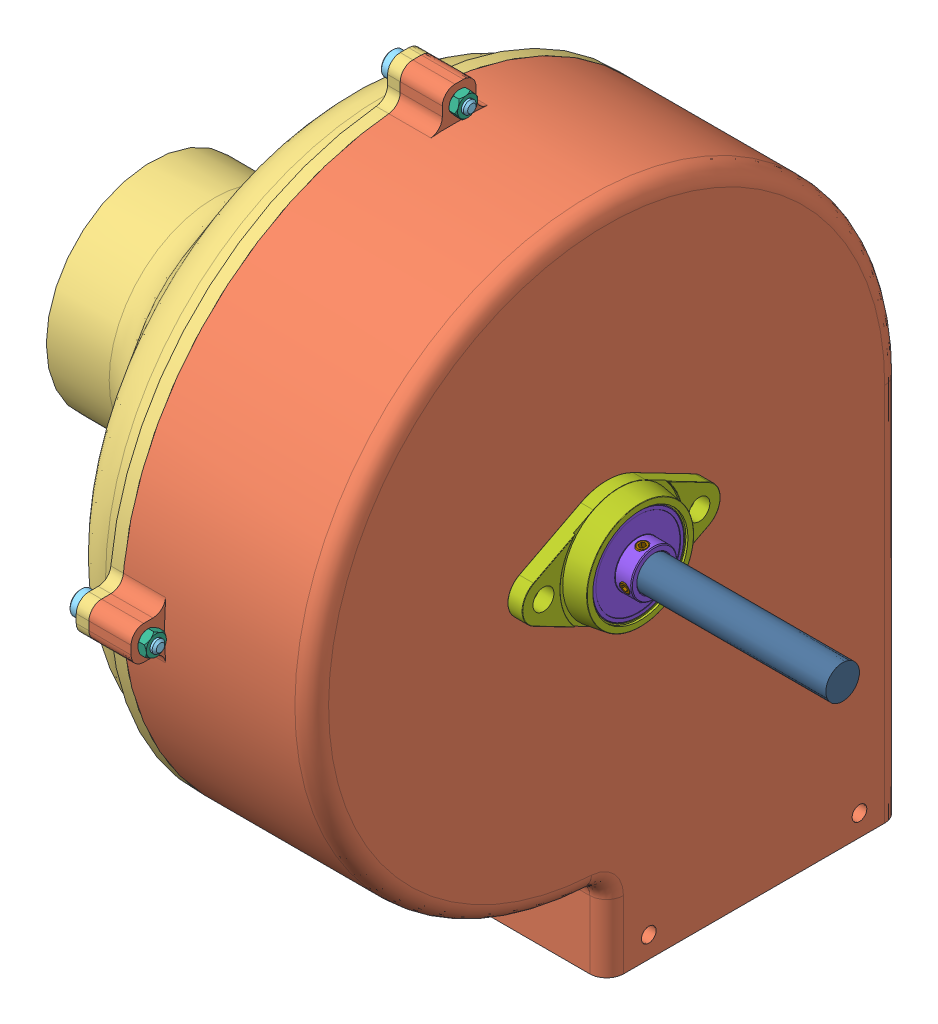
SolidWorks assembly blower, configuration Default. Lengths in mm.
Overall size (164 167.89 155.89).
20 component instances, 10 part files, 34 mates.
Components (placement in the parent):
- impeller-1: impeller [Default] at (-69.6752 187.7054 -326.6035) x (0 0.998096 -0.061685) z (0 0.061685 0.998096) size (118 42 118)
- bottom-1: bottom [external-motor] at (-57.6752 187.7054 -326.6035) x (0 0 -1) z (0 1 0) size (155.89 45 167.89)
- top-1: top [Default] at (-102.6752 187.7054 -326.6035) x (0 -1 0) z (0 0 -1) size (167.89 63 155.89)
- rotating-body^blower-1: rotating-body^blower [Default] at (-69.6752 187.7054 -326.6035) x (0 -0.998096 0.061685) z (1 0 0) size (120 120 42) (virtual)
- m3-socket-16-1: m3-socket-16 [Default] at (-108.6752 114.164 -400.6035) size (19 5.5 5.5)
- m3-socket-16-2: m3-socket-16 [Default] at (-108.6752 114.164 -322.6035) size (19 5.5 5.5)
- m3-socket-16-3: m3-socket-16 [Default] at (-108.6752 183.7054 -400.6035) size (19 5.5 5.5)
- m3-socket-16-4: m3-socket-16 [Default] at (-108.6752 261.591 -326.6035) size (19 5.5 5.5)
- m3-socket-16-6: m3-socket-16 [Default] at (-108.6752 187.7054 -252.7179) size (19 5.5 5.5)
- m3-nut-1: m3-nut [Default] at (-91.6752 114.164 -322.6035) x (0 0 -1) z (-1 0 0) size (5.8 5.57 2.34)
- m3-nut-2: m3-nut [Default] at (-91.6752 114.164 -400.6035) x (0 -0.187502 0.982264) z (-1 0 0) size (5.8 5.57 2.34)
- m3-nut-3: m3-nut [Default] at (-91.6752 261.591 -326.6035) x (0 0.140069 0.990142) z (-1 0 0) size (5.8 5.57 2.34)
- m3-nut-4: m3-nut [Default] at (-91.6752 183.7054 -400.6035) x (0 0 1) z (-1 0 0) size (5.8 5.57 2.34)
- m3-nut-5: m3-nut [Default] at (-91.6752 187.7054 -252.7179) x (0 0.924225 0.381849) z (1 0 0) size (5.8 5.57 2.34)
- KFL08-1: KFL08 [Valor predeterminado] at (-51.6128 189.1686 -373.1035) x (0 -1 0) z (0 0 1) size (27 11.38 47)
  - KFL08-1: KFL08 [Valor predeterminado] at (1.4633 -6.0625 46.5) size (27 8.03 47)
  - 608RS-1: 608RS [Default] at (1.4633 -5.5625 46.5) x (1 0 0) z (0 1 0) size (22 22 10.85)
  - MOSCAM2,5-4: MOSCAM2,5 [Valor predeterminado] at (3.1942 3.5013 53.231) x (-0.249054 0 -0.96849) z (0.96849 0 -0.249054) size (1.5 2.71 2.71)
  - MOSCAM2,5-5: MOSCAM2,5 [Valor predeterminado] at (-5.3662 3.4043 47.7886) x (0.982661 0 -0.185412) z (0.185412 0 0.982661) size (1.5 2.71 2.71)
- steel-rod-8mm-100mm-1: steel-rod-8mm-100mm [Default] at (-101.6752 187.7054 -326.6035) x (0 0.372382 -0.928079) z (0 -0.928079 -0.372382) size (8 100 8)
Mates (geometry in assembly coordinates):
- Concentric1: concentric aligned: cylinder of xd3420_motor-1 through (-89.6752 187.7054 -326.6035) axis (1 0 0) radius 4; cylinder of impeller-1 through (-81.6752 187.7054 -326.6035) axis (1 0 0) radius 4
- Coincident4: coincident anti-aligned: plane of bottom-1 through (-102.6752 187.7054 -326.6035) normal (-1 0 0); plane of top-1 through (-102.6752 187.7054 -326.6035) normal (1 0 0)
- Coincident5: coincident aligned: plane of bottom-1 through (-60.6752 97.7054 -396.6035) normal (0 -1 0); plane of top-1 through (-105.6752 97.7054 -396.6035) normal (0 -1 0)
- Coincident6: coincident aligned: plane of bottom-1 through (-60.6752 187.7054 -396.6035) normal (0 0 -1); plane of top-1 through (-105.6752 187.7054 -396.6035) normal (0 0 -1)
- InPlace3: in place: plane of ? through (-69.6752 187.7054 -326.6035) normal (1 0 0); plane of ? through (-69.6752 0 0) normal (1 0 0); moOrthogonalPlaneRef_w of ? through (-69.6752 187.7054 -326.6035) normal (1 0 0); plane of ? through (-69.6752 0 0) normal (0 1 0); plane of ? through (-69.6752 187.7054 -326.6035) normal (1 0 0); plane of ? through (-69.6752 0 0) normal (0 0 -1); plane of impeller-1 through (-69.6752 187.7054 -326.6035) normal (1 0 0); unknown of rotating-body^blower-1
- Coincident74: coincident aligned: plane of impeller-1; plane of rotating-body^blower-1
- Coincident75: coincident aligned: moOrthogonalPlaneRef_w of impeller-1; plane of rotating-body^blower-1 through (-69.6752 187.7054 -326.6035) normal (0 -0.061685 -0.998096)
- Coincident76: coincident anti-aligned: moOrthogonalPlaneRef_w of impeller-1; plane of rotating-body^blower-1 through (-69.6752 187.7054 -326.6035) normal (0 -0.998096 0.061685)
- Distance1: distance = 2 mm anti-aligned: plane of impeller-1 through (-69.6752 187.7054 -326.6035) normal (1 0 0); plane of xd3420_motor-1 through (-67.6752 187.7054 -347.1035) normal (-1 0 0)
- Coincident7: coincident anti-aligned: plane of top-1 through (-105.6752 187.7054 -326.6035) normal (-1 0 0); plane of m3-socket-16-1 through (-105.6752 115.654 -400.6035) normal (1 0 0)
- Concentric4: concentric anti-aligned: cylinder of m3-socket-16-1 through (-197.3807 114.164 -400.6035) axis (-1 0 0) radius 1.49; cylinder of top-1 through (-116.989 114.164 -400.6035) axis (1 0 0) radius 1.75
- Concentric5: concentric anti-aligned: cylinder of top-1 through (-116.989 183.7054 -400.6035) axis (1 0 0) radius 1.75; cylinder of m3-socket-16-3 through (-197.3807 183.7054 -400.6035) axis (-1 0 0) radius 1.49
- Coincident8: coincident anti-aligned: plane of top-1 through (-105.6752 187.7054 -326.6035) normal (-1 0 0); plane of m3-socket-16-3 through (-105.6752 185.1954 -400.6035) normal (1 0 0)
- Concentric6: concentric anti-aligned: cylinder of top-1 through (-116.989 261.591 -326.6035) axis (1 0 0) radius 1.75; cylinder of m3-socket-16-4 through (-197.3807 261.591 -326.6035) axis (-1 0 0) radius 1.49
- Coincident9: coincident anti-aligned: plane of top-1 through (-105.6752 187.7054 -326.6035) normal (-1 0 0); plane of m3-socket-16-4 through (-105.6752 263.081 -326.6035) normal (1 0 0)
- Concentric7: concentric anti-aligned: cylinder of top-1 through (-116.989 187.7054 -252.7179) axis (1 0 0) radius 1.75; cylinder of m3-socket-16-6 through (-197.3807 187.7054 -252.7179) axis (-1 0 0) radius 1.49
- Coincident10: coincident anti-aligned: plane of top-1 through (-105.6752 187.7054 -326.6035) normal (-1 0 0); plane of m3-socket-16-6 through (-105.6752 189.1954 -252.7179) normal (1 0 0)
- Coincident11: coincident anti-aligned: plane of top-1 through (-105.6752 187.7054 -326.6035) normal (-1 0 0); plane of m3-socket-16-2 through (-105.6752 115.654 -322.6035) normal (1 0 0)
- Concentric8: concentric anti-aligned: cylinder of top-1 through (-116.989 114.164 -322.6035) axis (1 0 0) radius 1.75; cylinder of m3-socket-16-2 through (-197.3807 114.164 -322.6035) axis (-1 0 0) radius 1.49
- Coincident12: coincident anti-aligned: plane of bottom-1 through (-92.6752 187.7054 -326.6035) normal (1 0 0); plane of m3-nut-1 through (-92.6752 114.164 -322.6035) normal (-1 0 0)
- Concentric9: concentric anti-aligned: circle of bottom-1; circle of m3-nut-1
- Coincident13: coincident anti-aligned: plane of bottom-1 through (-92.6752 187.7054 -326.6035) normal (1 0 0); plane of m3-nut-5 through (-92.6752 187.7054 -252.7179) normal (-1 0 0)
- Concentric10: concentric aligned: circle of bottom-1; circle of m3-nut-5
- Concentric11: concentric anti-aligned: circle of bottom-1; circle of m3-nut-3
- Coincident14: coincident anti-aligned: plane of bottom-1 through (-92.6752 187.7054 -326.6035) normal (1 0 0); plane of m3-nut-3 through (-92.6752 261.591 -326.6035) normal (-1 0 0)
- Coincident15: coincident anti-aligned: plane of bottom-1 through (-92.6752 187.7054 -326.6035) normal (1 0 0); plane of m3-nut-4 through (-92.6752 183.7054 -400.6035) normal (-1 0 0)
- Concentric12: concentric anti-aligned: cylinder of bottom-1 through (-92.6752 183.7054 -400.6035) axis (-1 0 0) radius 1.75; circle of m3-nut-4
- Concentric13: concentric anti-aligned: cylinder of bottom-1 through (-92.6752 114.164 -400.6035) axis (-1 0 0) radius 1.75; circle of m3-nut-2
- Coincident16: coincident anti-aligned: plane of bottom-1 through (-92.6752 187.7054 -326.6035) normal (1 0 0); plane of m3-nut-2 through (-92.6752 114.164 -400.6035) normal (-1 0 0)
- Coincident112: coincident anti-aligned: plane of bottom-1 through (-57.6752 187.7054 -326.6035) normal (1 0 0); plane of KFL08-1/KFL08-1 through (-57.6752 187.7054 -326.6035) normal (-1 0 0)
- Concentric23: concentric anti-aligned: cylinder of bottom-1 through (-60.6752 187.7054 -308.1035) axis (1 0 0) radius 2.5; cylinder of KFL08-1/KFL08-1 through (-54.6752 187.7054 -308.1035) axis (-1 0 0) radius 2.5
- Concentric21: concentric anti-aligned: cylinder of impeller-1 through (-81.6752 187.7054 -326.6035) axis (1 0 0) radius 4; cylinder of steel-rod-8mm-100mm-1 through (-1.6752 187.7054 -326.6035) axis (-1 0 0) radius 4
- Distance3: distance = 20 mm aligned: plane of steel-rod-8mm-100mm-1 through (-101.6752 187.7054 -326.6035) normal (-1 0 0); plane of impeller-1 through (-81.6752 187.7054 -326.6035) normal (-1 0 0)
- Concentric25: concentric aligned: cylinder of steel-rod-8mm-100mm-1 through (-1.6752 187.7054 -326.6035) axis (-1 0 0) radius 4; cylinder of KFL08-1/608RS-1 through (-50.1752 187.7054 -326.6035) axis (-1 0 0) radius 4
